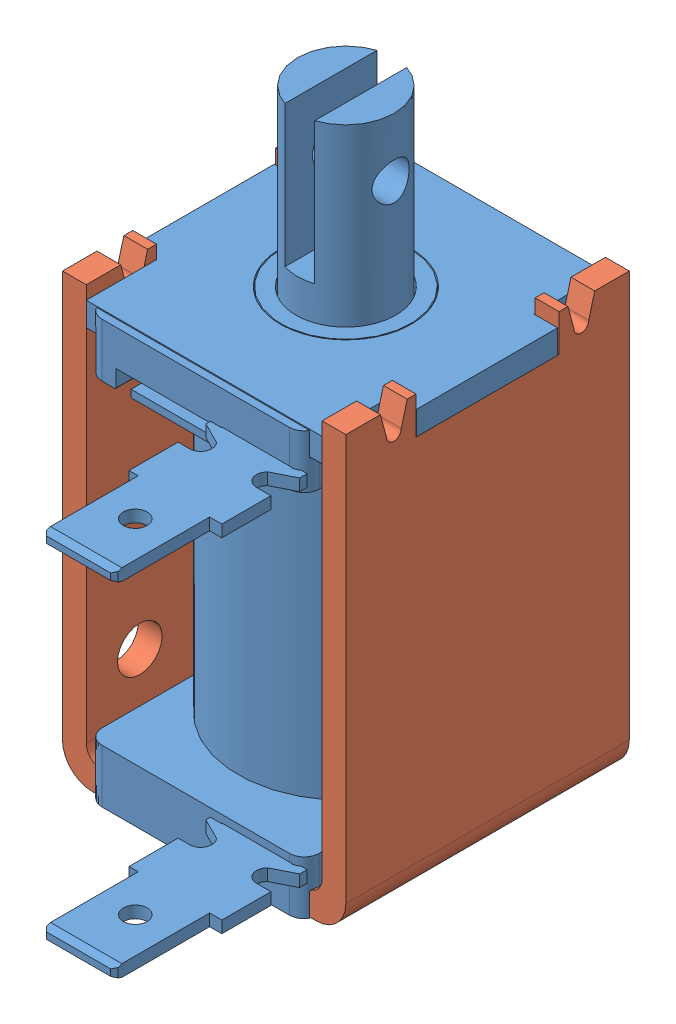
SolidWorks assembly DSOL-0630-12E - SOLENOID, OPEN-FRAME, PULL, INTERMITTENT, 12V, .50 STROKE, configuration Default. Lengths in mm.
Overall size (19.05 40.9 31.63).
2 component instances, 2 part files, 0 mates.
Components (placement in the parent):
- COPPER_WIRE-DSOS-0630-24-1: COPPER_WIRE-DSOS-0630-24 [Default] at (0 3.6 0) size (19.05 40.9 31.63)
- U-FRAME_DSOS-0630-24-1: U-FRAME_DSOS-0630-24 [Default] at origin size (19.05 29.3 19.05)
